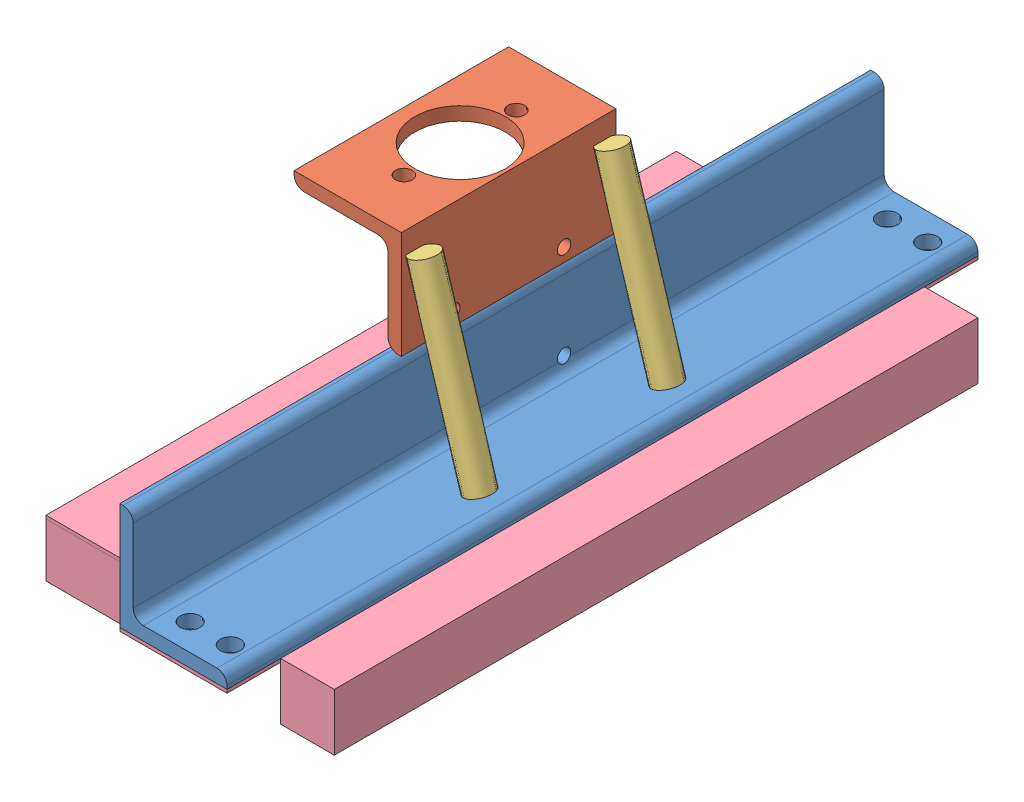
SolidWorks assembly 01-048-00-0, configuration Default. Lengths in mm.
Overall size (279.4 257.18 711.2).
5 component instances, 4 part files, 6 mates.
Components (placement in the parent):
- 01-042-00-0-1: 01-042-00-0 [Default] at origin size (101.6 101.6 711.2)
- 01-043-00-0-1: 01-043-00-0 [Default] at (12.7 203.2 0) x (-1 0 0) z (0 0 1) size (101.6 101.6 203.2)
- 01-047-00-0-5: 01-047-00-0 [Default] at (74.1068 15.97 -88.9) x (0.948496 0.291905 -0.123074) z (0.11763 0.036201 0.992397) size (25.4 177.8 25.4)
- 01-047-00-0-7: 01-047-00-0 [Default] at (74.1066 15.5263 89.0193) x (0.948496 0.291905 -0.123074) z (0.11763 0.036201 0.992397) size (25.4 177.8 25.4)
- 01-074-00-0-1: 01-074-00-0 [Default] at (0 -3.175 298.45) x (0 0 -1) z (1 0 0) size (711.2 53.98 279.4)
Mates (geometry in assembly coordinates):
- Coincident1: coincident aligned: plane of 01-042-00-0-1 through (0 0 355.6) normal (-1 0 0); plane of 01-043-00-0-1 through (0 111.1199 101.6) normal (-1 0 0)
- Coincident2: coincident anti-aligned: plane of 01-042-00-0-1 through (0 101.6 355.6) normal (0 1 0); plane of 01-043-00-0-1 through (12.7 101.6 101.6) normal (0 -1 0)
- Distance1: distance = 254 mm aligned: plane of 01-042-00-0-1 through (3.1801 92.0801 355.6) normal (0 0 1); plane of 01-043-00-0-1 through (9.5199 111.1199 101.6) normal (0 0 1)
- Coincident287: coincident: moEndPointRef_w of 01-074-00-0-1; plane of assembly
- Coincident292: coincident anti-aligned: plane of 01-042-00-0-1 through (0 0 355.6) normal (-1 0 0); plane of 01-074-00-0-1 through (0 0 -76.2) normal (1 0 0)
- Coincident293: coincident anti-aligned: plane of 01-042-00-0-1 through (101.6 0 355.6) normal (0 -1 0); plane of 01-074-00-0-1 through (-127 0 298.45) normal (0 1 0)
